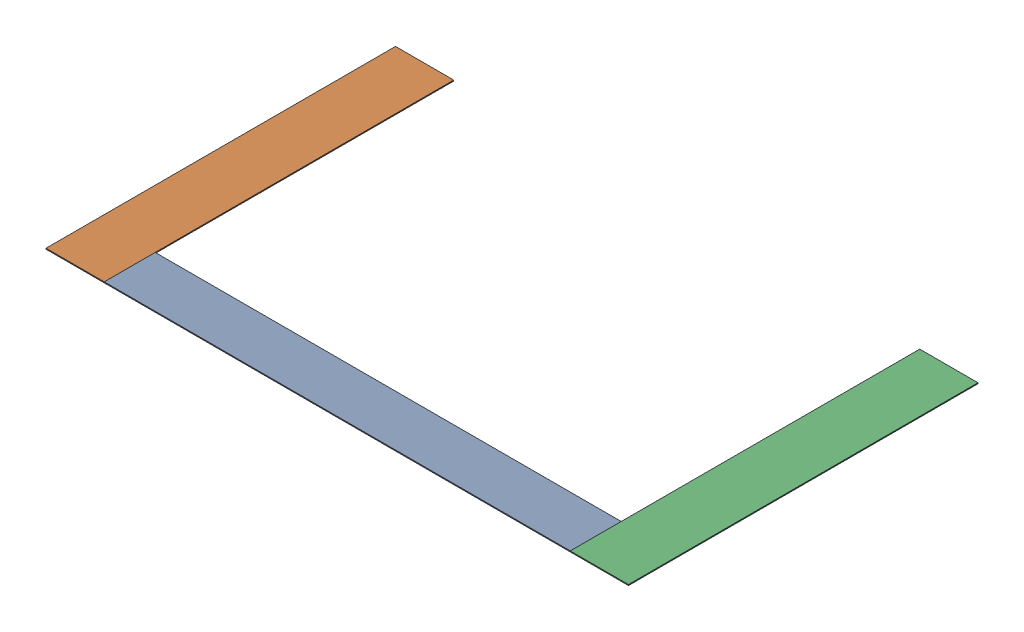
SolidWorks assembly GE-16004-01_ASM, configuration Default. Lengths in mm.
Overall size (508 0.79 304.8).
3 component instances, 2 part files, 0 mates.
Components (placement in the parent):
- GE-16004-02-1: GE-16004-02 [Default] at origin size (406.4 0.79 44.45)
- GE-16004-03-1: GE-16004-03 [Default] at (-228.6 0 -130.175) x (0 0 -1) z (1 0 0) size (304.8 0.79 50.8)
- GE-16004-03-2: GE-16004-03 [Default] at (228.6 0 -130.175) x (0 0 -1) z (1 0 0) size (304.8 0.79 50.8)
